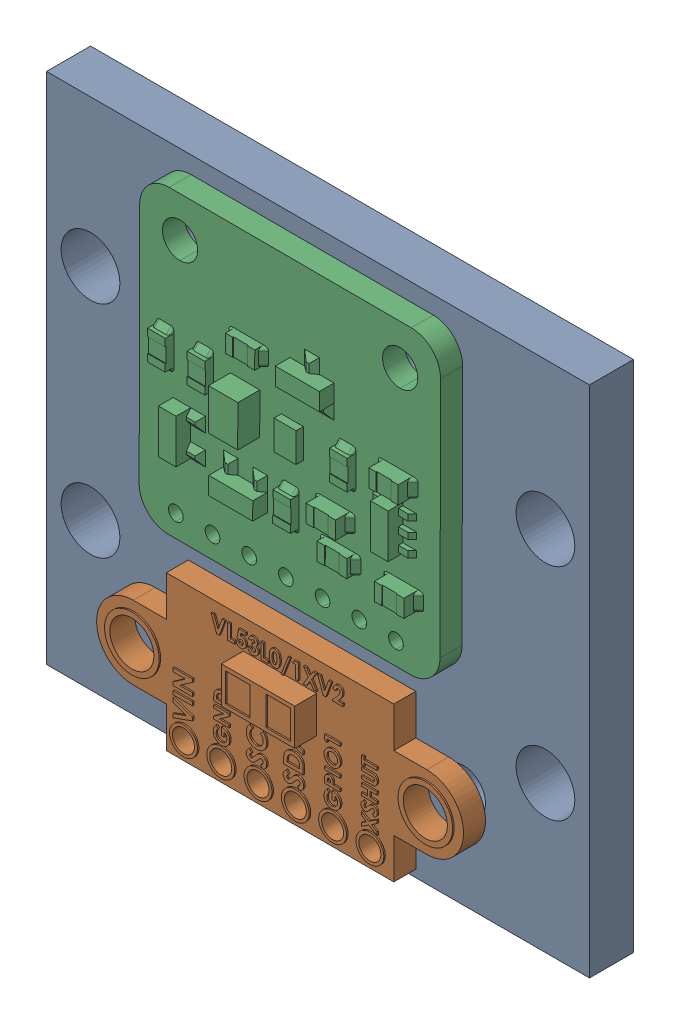
SolidWorks assembly Holder, configuration Default. Lengths in mm.
Overall size (37 35 7).
3 component instances, 3 part files, 2 mates.
Components (placement in the parent):
- Color sensor bracket-1: Color sensor bracket [Default] at (2.9911 -5.7777 2.3469) size (37 35 3)
- VL53l1X-1: VL53l1X [Varsayılan] at (2.9366 -10.6051 6.3469) x (1 0 0) z (0 -1 0) size (25 4 10.5)
- tcs34725_rgb_sensor-3: tcs34725_rgb_sensor [Default] at (2.6045 6.2133 5.3469) x (0.002325 0.999997 0) z (0.999997 -0.002325 0) size (20.51 3 20.51)
Mates (geometry in assembly coordinates):
- Coincident1: coincident anti-aligned: plane of Color sensor bracket-1 through (2.9911 -5.7777 5.3469) normal (0 0 1); plane of VL53l1X-1 through (2.9366 -10.6051 5.3469) normal (0 0 -1)
- Tangent8: tangent anti-aligned: plane of Color sensor bracket-1 through (2.9911 -5.7777 5.3469) normal (0 0 1); face of tcs34725_rgb_sensor-3
